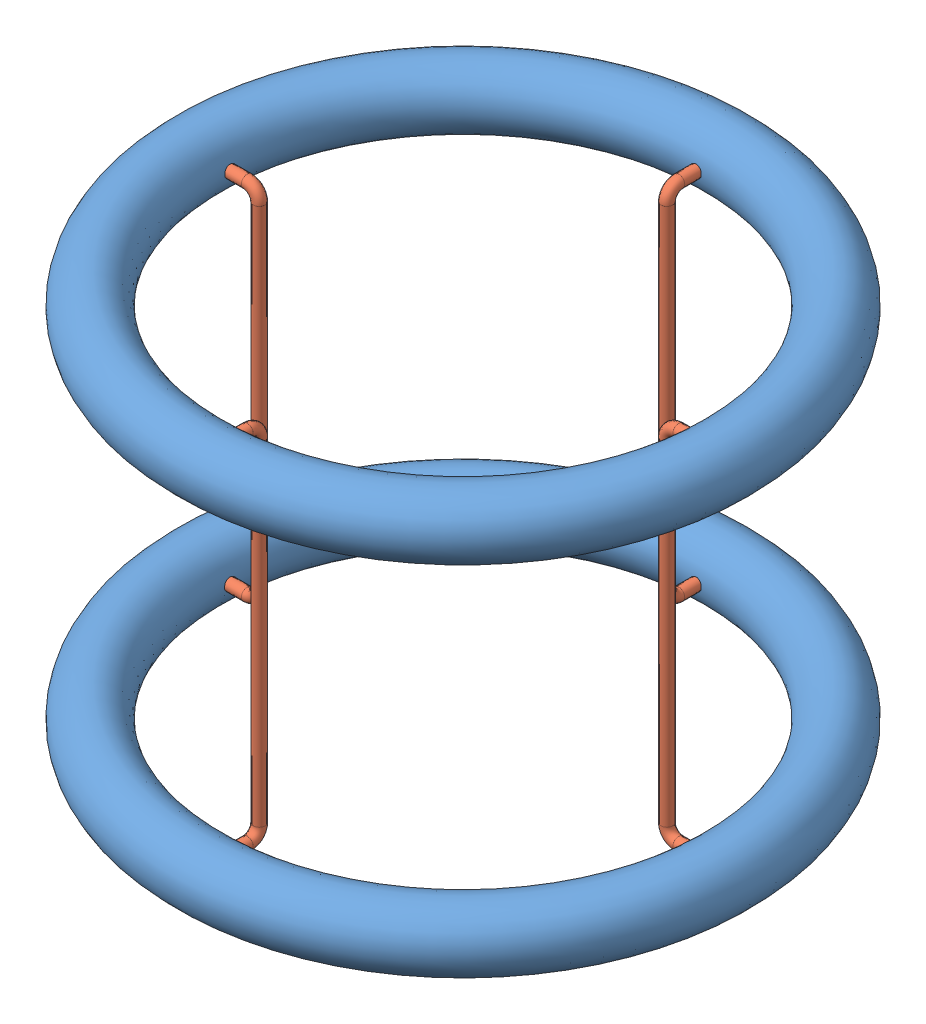
SolidWorks assembly Baugr1, configuration Standard. Lengths in mm.
Overall size (1385.78 705 1385.78).
6 component instances, 2 part files, 2 mates.
Components (placement in the parent):
- Torus_D_85mm-1: Torus_D_85mm [Standard] at (-64.9459 8.1182 990) size (990 105 990)
- Torus_D_85mm-2: Torus_D_85mm [Standard] at (-64.9459 608.1182 990) x (0.80066 0 0.599119) z (-0.599119 0 0.80066) size (990 105 990)
- Träger_Torus_600mm-1: Träger_Torus_600mm [Standard] at (302.0188 308.1182 990) size (60 620 20)
- Träger_Torus_600mm-2: Träger_Torus_600mm [Standard] at (-64.9459 308.1182 623.0353) x (0 0 -1) z (1 0 0) size (60 620 20)
- Träger_Torus_600mm-3: Träger_Torus_600mm [Standard] at (-431.9106 308.1182 990) x (-1 0 0) z (0 0 -1) size (60 620 20)
- Träger_Torus_600mm-4: Träger_Torus_600mm [Standard] at (-64.9459 308.1182 1356.9647) x (0 0 1) z (-1 0 0) size (60 620 20)
Mates (geometry in assembly coordinates):
- Abstand1: distance = 600 mm: point of Torus_D_85mm-1; point of Torus_D_85mm-2
- Deckungsgleich5: coincident anti-aligned: line of Torus_D_85mm-1 through (-609.4459 8.1182 990) axis (1 0 0); line of Träger_Torus_600mm-1 through (617.8856 8.1182 990) axis (-1 0 0)
